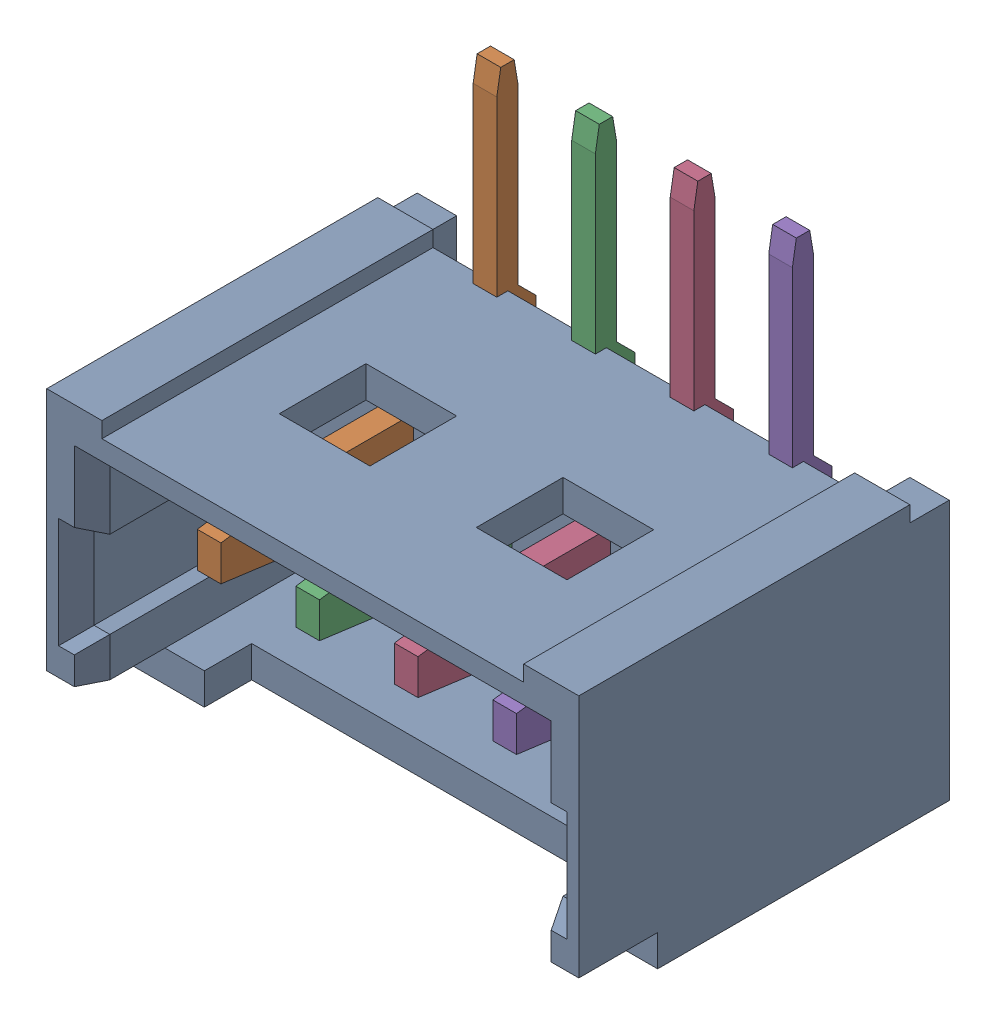
SolidWorks assembly 653004117322, configuration Default. Lengths in mm.
Overall size (6.75 5.8 4.7).
5 component instances, 2 part files, 0 mates.
Components (placement in the parent):
- 653004117322-1: 653004117322 [Default] at origin size (6.75 3.5 4.7)
- 6530xx117322_PIN-1: 6530xx117322_PIN [Default] at (-1.875 0.375 -1.96) size (0.3 4.9 4)
- 6530xx117322_PIN-2: 6530xx117322_PIN [Default] at (-0.625 0.375 -1.96) size (0.3 4.9 4)
- 6530xx117322_PIN-3: 6530xx117322_PIN [Default] at (0.625 0.375 -1.96) size (0.3 4.9 4)
- 6530xx117322_PIN-4: 6530xx117322_PIN [Default] at (1.875 0.375 -1.96) size (0.3 4.9 4)
